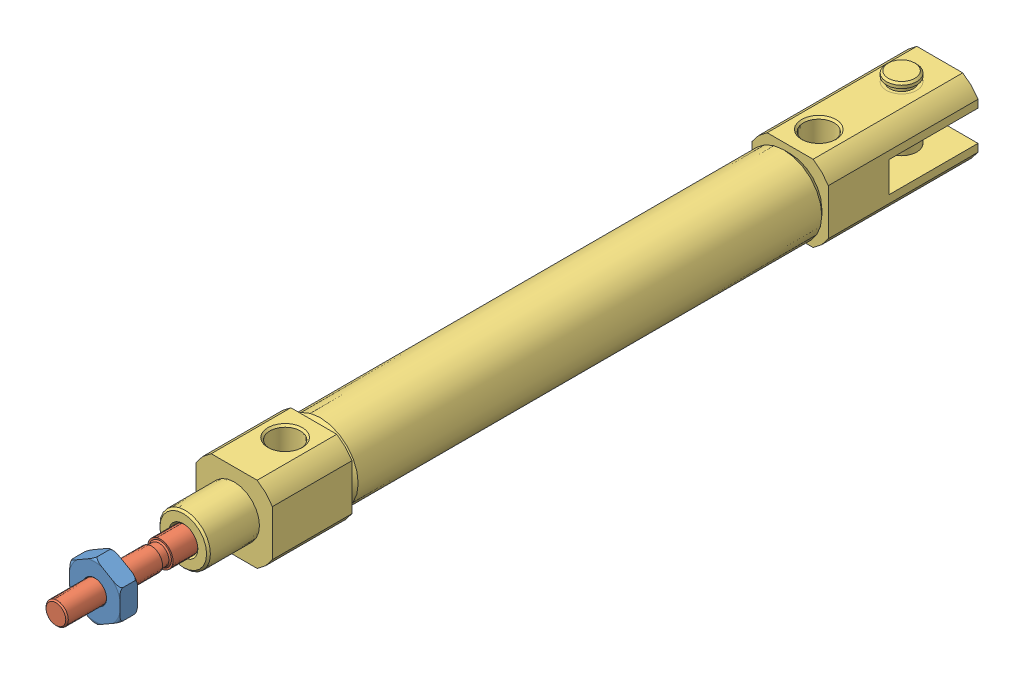
SolidWorks assembly NCJ2D10-200, configuration Default. Lengths in mm.
Overall size (12 14.99 138.8).
3 component instances, 3 part files, 0 mates.
Components (placement in the parent):
- NCJ2D10-200.step_NCJ2-Nut_10R-1: NCJ2D10-200.step_NCJ2-Nut_10R [Default] at (0 0 70.4) size (8.86 9.6 3.3)
- NCJ2D10-200.step_NCJ2-Rod_10-1: NCJ2D10-200.step_NCJ2-Rod_10 [Default] at (0 0 -25.4) size (10 10 105.8)
- NCJ2D10-200.step_NCJ2-Body_10D-1: NCJ2D10-200.step_NCJ2-Body_10D [Default] at origin size (12 14.99 118.8)
